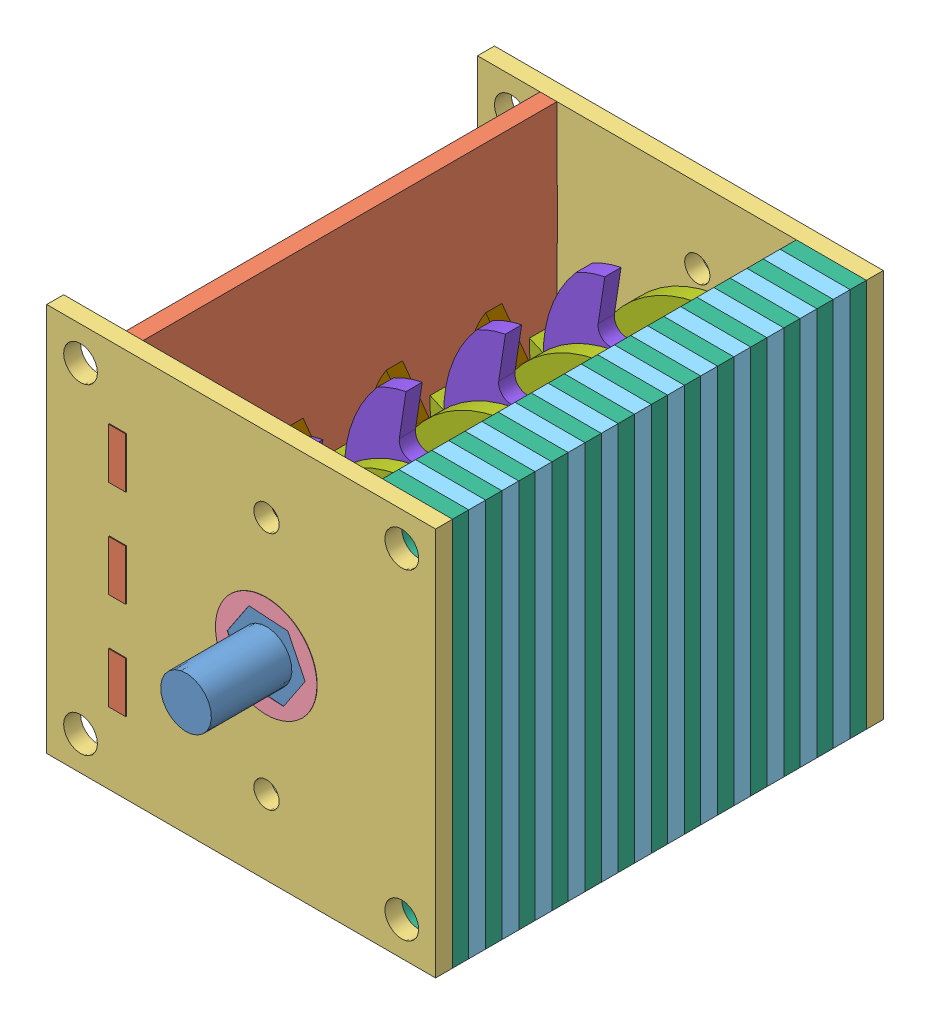
SolidWorks assembly Assem1, configuration Default. Lengths in mm.
Overall size (146.05 146.05 228.6).
56 component instances, 9 part files, 47 mates.
Components (placement in the parent):
- Axle-1: Axle [Default] at (0 0 80.899) x (-0.064462 -0.99792 0) z (0 0 1) size (25.4 29.33 228.6)
- BackPlate-1: BackPlate [Default] at (-55.88 0 80.899) x (0 0 -1) z (1 0 0) size (168.66 146.05 6.35)
- Side_Plate-1: Side_Plate [Default] at origin size (146.05 146.05 6.35)
- Side_Plate-2: Side_Plate [Default] at (0 0 161.798) size (146.05 146.05 6.35)
- Hex_Spacer-1: Hex_Spacer [Default] at (0 0 18.669) x (0.831993 -0.554786 0) z (0 0 1) size (38.1 38.1 6.35)
- Hex_Spacer-2: Hex_Spacer [Default] at (0 0 31.115) x (0.831993 -0.554786 0) z (0 0 1) size (38.1 38.1 6.35)
- Hex_Spacer-3: Hex_Spacer [Default] at (0 0 43.561) x (-0.831993 0.554786 0) z (0 0 1) size (38.1 38.1 6.35)
- Hex_Spacer-13: Hex_Spacer [Default] at (0 0 6.223) x (0.831993 -0.554786 0) z (0 0 1) size (38.1 38.1 6.35)
- Hex_Spacer-14: Hex_Spacer [Default] at (0 0 -0.127) x (0.831993 -0.554786 0) z (0 0 1) size (38.1 38.1 6.35)
- Hex_Spacer-15: Hex_Spacer [Default] at (0 0 161.925) x (0.831993 -0.554786 0) z (0 0 1) size (38.1 38.1 6.35)
- Spacer_1-1: Spacer_1 [Default] at (44.45 0 12.446) size (34.77 146.05 6.35)
- Spacer_2-1: Spacer_2 [Default] at (44.45 0 6.223) size (59.73 146.05 6.1)
- Spacer_2-14: Spacer_2 [Default] at (44.45 0 155.575) size (59.73 146.05 6.1)
- Spacer_2-2: Spacer_2 [Default] at (44.45 0 18.669) size (59.73 146.05 6.1)
- Spacer_2-3: Spacer_2 [Default] at (44.45 0 31.115) size (59.73 146.05 6.1)
- Spacer_2-4: Spacer_2 [Default] at (44.45 0 43.561) size (59.73 146.05 6.1)
- Spacer_2-5: Spacer_2 [Default] at (44.45 0 56.007) size (59.73 146.05 6.1)
- Spacer_2-6: Spacer_2 [Default] at (44.45 0 68.453) size (59.73 146.05 6.1)
- Spacer_2-7: Spacer_2 [Default] at (44.45 0 80.899) size (59.73 146.05 6.1)
- Spacer_2-8: Spacer_2 [Default] at (44.45 0 93.345) size (59.73 146.05 6.1)
- Spacer_2-9: Spacer_2 [Default] at (44.45 0 105.791) size (59.73 146.05 6.1)
- Spacer_2-10: Spacer_2 [Default] at (44.45 0 118.237) size (59.73 146.05 6.1)
- Spacer_2-11: Spacer_2 [Default] at (44.45 0 130.683) size (59.73 146.05 6.1)
- Spacer_2-12: Spacer_2 [Default] at (44.45 0 143.129) size (59.73 146.05 6.1)
- Spacer_1-3: Spacer_1 [Default] at (44.45 0 24.892) size (34.77 146.05 6.35)
- Spacer_1-4: Spacer_1 [Default] at (44.45 0 37.338) size (34.77 146.05 6.35)
- Spacer_1-5: Spacer_1 [Default] at (44.45 0 49.784) size (34.77 146.05 6.35)
- Spacer_1-6: Spacer_1 [Default] at (44.45 0 62.23) size (34.77 146.05 6.35)
- Spacer_1-7: Spacer_1 [Default] at (44.45 0 74.676) size (34.77 146.05 6.35)
- Spacer_1-8: Spacer_1 [Default] at (44.45 0 87.122) size (34.77 146.05 6.35)
- Spacer_1-9: Spacer_1 [Default] at (44.45 0 99.568) size (34.77 146.05 6.35)
- Spacer_1-10: Spacer_1 [Default] at (44.45 0 112.014) size (34.77 146.05 6.35)
- Spacer_1-11: Spacer_1 [Default] at (44.45 0 124.46) size (34.77 146.05 6.35)
- Spacer_1-12: Spacer_1 [Default] at (44.45 0 136.906) size (34.77 146.05 6.35)
- Spacer_1-13: Spacer_1 [Default] at (44.45 0 149.352) size (34.77 146.05 6.35)
- Cutter_1-1: Cutter_1 [Default] at (0 0 12.446) x (-0.064462 -0.99792 0) z (0.99792 -0.064462 0) size (280.09 6.1 281.96)
- Cutter_2-1: Cutter_2 [Default] at (0 0 24.892) x (0.660055 -0.751218 0) z (0.751218 0.660055 0) size (280.09 6.1 281.96)
- Cutter_3-1: Cutter_3 [Default] at (0 0 37.338) x (0.99792 -0.064462 0) z (0.064462 0.99792 0) size (280.09 6.1 281.96)
- Hex_Spacer-4: Hex_Spacer [Default] at (0 0 80.899) x (-0.831993 0.554786 0) z (0 0 1) size (38.1 38.1 6.35)
- Hex_Spacer-5: Hex_Spacer [Default] at (0 0 118.237) x (-0.831993 0.554786 0) z (0 0 1) size (38.1 38.1 6.35)
- Hex_Spacer-6: Hex_Spacer [Default] at (0 0 155.575) x (-0.831993 0.554786 0) z (0 0 1) size (38.1 38.1 6.35)
- Hex_Spacer-7: Hex_Spacer [Default] at (0 0 68.453) x (0.831993 -0.554786 0) z (0 0 1) size (38.1 38.1 6.35)
- Hex_Spacer-8: Hex_Spacer [Default] at (0 0 105.791) x (0.831993 -0.554786 0) z (0 0 1) size (38.1 38.1 6.35)
- Hex_Spacer-9: Hex_Spacer [Default] at (0 0 143.129) x (0.831993 -0.554786 0) z (0 0 1) size (38.1 38.1 6.35)
- Hex_Spacer-10: Hex_Spacer [Default] at (0 0 56.007) x (0.831993 -0.554786 0) z (0 0 1) size (38.1 38.1 6.35)
- Hex_Spacer-11: Hex_Spacer [Default] at (0 0 93.345) x (0.831993 -0.554786 0) z (0 0 1) size (38.1 38.1 6.35)
- Hex_Spacer-12: Hex_Spacer [Default] at (0 0 130.683) x (0.831993 -0.554786 0) z (0 0 1) size (38.1 38.1 6.35)
- Cutter_3-2: Cutter_3 [Default] at (0 0 74.676) x (0.99792 -0.064462 0) z (0.064462 0.99792 0) size (280.09 6.1 281.96)
- Cutter_3-3: Cutter_3 [Default] at (0 0 112.014) x (0.99792 -0.064462 0) z (0.064462 0.99792 0) size (280.09 6.1 281.96)
- Cutter_3-4: Cutter_3 [Default] at (0 0 149.352) x (0.99792 -0.064462 0) z (0.064462 0.99792 0) size (280.09 6.1 281.96)
- Cutter_2-2: Cutter_2 [Default] at (0 0 62.23) x (0.660055 -0.751218 0) z (0.751218 0.660055 0) size (280.09 6.1 281.96)
- Cutter_2-3: Cutter_2 [Default] at (0 0 99.568) x (0.660055 -0.751218 0) z (0.751218 0.660055 0) size (280.09 6.1 281.96)
- Cutter_2-4: Cutter_2 [Default] at (0 0 136.906) x (0.660055 -0.751218 0) z (0.751218 0.660055 0) size (280.09 6.1 281.96)
- Cutter_1-2: Cutter_1 [Default] at (0 0 49.784) x (-0.064462 -0.99792 0) z (0.99792 -0.064462 0) size (280.09 6.1 281.96)
- Cutter_1-3: Cutter_1 [Default] at (0 0 87.122) x (-0.064462 -0.99792 0) z (0.99792 -0.064462 0) size (280.09 6.1 281.96)
- Cutter_1-4: Cutter_1 [Default] at (0 0 124.46) x (-0.064462 -0.99792 0) z (0.99792 -0.064462 0) size (280.09 6.1 281.96)
Mates (geometry in assembly coordinates):
- Coincident15: coincident: plane of BackPlate-1 through (-55.88 0 80.899) normal (0 1 0); plane of assembly through (0 0 0) normal (0 1 0)
- Coincident19: coincident: plane of Side_Plate-1 through (0 0 0) normal (0 0 1); plane of assembly through (0 0 0) normal (0 0 1)
- Coincident20: coincident: plane of Side_Plate-1 through (0 0 0) normal (1 0 0); plane of assembly through (0 0 0) normal (1 0 0)
- Coincident21: coincident: plane of Side_Plate-1 through (0 0 0) normal (0 1 0); plane of assembly through (0 0 0) normal (0 1 0)
- Coincident22: coincident: plane of BackPlate-1 through (-55.88 0 80.899) normal (1 0 0); plane of assembly through (-55.88 0 0) normal (1 0 0)
- Coincident23: coincident: plane of BackPlate-1 through (-52.705 73.025 3.175) normal (0 0 -1); plane of Side_Plate-1 through (0 0 3.175) normal (0 0 1)
- Concentric9: concentric: cylinder of Axle-1 through (0 0 195.199) axis (0 0 -1) radius 9.525; cylinder of Side_Plate-1 through (0 0 3.175) axis (0 0 -1) radius 19.05
- Coincident25: coincident: line of Axle-1 through (-6.4984 13.1462 164.973) axis (0 0 -1); line of Hex_Spacer-1 through (-6.4984 13.1462 21.844) axis (0 0 -1)
- Coincident26: coincident: line of Axle-1 through (6.4984 -13.1462 164.973) axis (0 0 -1); line of Hex_Spacer-1 through (6.4984 -13.1462 21.844) axis (0 0 -1)
- Concentric14: concentric: cylinder of Side_Plate-1 through (50.8 -60.325 3.175) axis (0 0 -1) radius 6.35; cylinder of Spacer_1-1 through (50.8 -60.325 15.621) axis (0 0 -1) radius 6.3627
- Coincident30: coincident: line of Axle-1 through (-6.4984 13.1462 164.973) axis (0 0 -1); line of Cutter_1-1 through (-6.4984 13.1462 9.398) axis (0 0 1)
- Coincident31: coincident: line of Axle-1 through (14.6342 -0.9453 164.973) axis (0 0 -1); line of Cutter_1-1 through (14.6342 -0.9453 9.398) axis (0 0 1)
- Concentric15: concentric: cylinder of Side_Plate-1 through (50.8 60.325 3.175) axis (0 0 -1) radius 6.35; cylinder of Spacer_1-1 through (50.8 60.325 15.621) axis (0 0 -1) radius 6.3627
- Concentric16: concentric: cylinder of Side_Plate-1 through (50.8 60.325 3.175) axis (0 0 -1) radius 6.35; cylinder of Spacer_2-1 through (50.8 60.325 9.271) axis (0 0 -1) radius 6.3627
- Concentric17: concentric: cylinder of Side_Plate-1 through (50.8 -60.325 3.175) axis (0 0 -1) radius 6.35; cylinder of Spacer_2-1 through (50.8 -60.325 9.271) axis (0 0 -1) radius 6.3627
- Coincident38: coincident: plane of Side_Plate-1 through (0 0 3.175) normal (0 0 1); plane of Spacer_2-1 through (44.45 0 3.175) normal (0 0 -1)
- Coincident39: coincident: plane of Spacer_1-1 through (44.45 0 9.271) normal (0 0 -1); plane of Spacer_2-1 through (44.45 0 9.271) normal (0 0 1)
- Coincident40: coincident: plane of Spacer_1-13 through (44.45 0 152.527) normal (0 0 1); plane of Spacer_2-14 through (44.45 0 152.527) normal (0 0 -1)
- Concentric19: concentric: cylinder of Side_Plate-1 through (50.8 -60.325 3.175) axis (0 0 -1) radius 6.35; cylinder of Spacer_2-14 through (50.8 -60.325 158.623) axis (0 0 -1) radius 6.3627
- Concentric20: concentric: cylinder of Side_Plate-1 through (50.8 60.325 3.175) axis (0 0 -1) radius 6.35; cylinder of Spacer_2-14 through (50.8 60.325 158.623) axis (0 0 -1) radius 6.3627
- Coincident41: coincident: plane of Spacer_2-14 through (44.45 0 158.623) normal (0 0 1); plane of Side_Plate-2 through (0 0 158.623) normal (0 0 -1)
- Concentric22: concentric: cylinder of Side_Plate-1 through (50.8 60.325 3.175) axis (0 0 -1) radius 6.35; cylinder of Side_Plate-2 through (50.8 60.325 164.973) axis (0 0 -1) radius 6.35
- Concentric23: concentric: cylinder of Side_Plate-1 through (50.8 -60.325 3.175) axis (0 0 -1) radius 6.35; cylinder of Side_Plate-2 through (50.8 -60.325 164.973) axis (0 0 -1) radius 6.35
- Coincident42: coincident: plane of Spacer_1-1 through (44.45 0 12.446) normal (0 0 1); plane of Cutter_1-1 through (0 0 12.446) normal (0 0 -1)
- Coincident43: coincident: plane of Hex_Spacer-1 through (0 0 15.494) normal (0 0 -1); plane of Cutter_1-1 through (0 0 15.494) normal (0 0 1)
- Coincident44: coincident: line of Axle-1 through (14.6342 -0.9453 164.973) axis (0 0 -1); line of Hex_Spacer-2 through (14.6342 -0.9453 34.29) axis (0 0 -1)
- Coincident45: coincident: line of Axle-1 through (-14.6342 0.9453 164.973) axis (0 0 -1); line of Hex_Spacer-2 through (-14.6342 0.9453 34.29) axis (0 0 -1)
- Coincident47: coincident: line of Axle-1 through (-14.6342 0.9453 164.973) axis (0 0 -1); line of Cutter_2-1 through (-14.6342 0.9453 21.844) axis (0 0 1)
- Coincident48: coincident: line of Axle-1 through (6.4984 -13.1462 164.973) axis (0 0 -1); line of Cutter_2-1 through (6.4984 -13.1462 21.844) axis (0 0 1)
- Coincident49: coincident: plane of Hex_Spacer-1 through (0 0 21.844) normal (0 0 1); plane of Cutter_2-1 through (0 0 21.844) normal (0 0 -1)
- Coincident50: coincident: plane of Hex_Spacer-2 through (0 0 27.94) normal (0 0 -1); plane of Cutter_2-1 through (0 0 27.94) normal (0 0 1)
- Coincident51: coincident: line of Axle-1 through (14.6342 -0.9453 164.973) axis (0 0 -1); line of Cutter_3-1 through (14.6342 -0.9453 34.29) axis (0 0 1)
- Coincident52: coincident: line of Axle-1 through (-8.1358 -12.2009 164.973) axis (0 0 -1); line of Cutter_3-1 through (-8.1358 -12.2009 34.29) axis (0 0 1)
- Coincident53: coincident: plane of Hex_Spacer-2 through (0 0 34.29) normal (0 0 1); plane of Cutter_3-1 through (0 0 34.29) normal (0 0 -1)
- Coincident54: coincident: line of Axle-1 through (-8.1358 -12.2009 164.973) axis (0 0 -1); line of Hex_Spacer-3 through (-8.1358 -12.2009 46.736) axis (0 0 -1)
- Coincident55: coincident: line of Axle-1 through (14.6342 -0.9453 164.973) axis (0 0 -1); line of Hex_Spacer-3 through (14.6342 -0.9453 46.736) axis (0 0 -1)
- Coincident56: coincident: plane of Cutter_3-1 through (0 0 40.386) normal (0 0 1); plane of Hex_Spacer-3 through (0 0 40.386) normal (0 0 -1)
- Coincident57: coincident: plane of Axle-1 through (0 0 -3.175) normal (0 0 -1); plane of Side_Plate-1 through (0 0 -3.175) normal (0 0 -1)
- Coincident58: coincident: line of Axle-1 through (14.6342 -0.9453 164.973) axis (0 0 -1); line of Hex_Spacer-13 through (14.6342 -0.9453 9.398) axis (0 0 -1)
- Coincident59: coincident: line of Axle-1 through (-14.6342 0.9453 164.973) axis (0 0 -1); line of Hex_Spacer-13 through (-14.6342 0.9453 9.398) axis (0 0 -1)
- Coincident60: coincident: plane of Cutter_1-1 through (0 0 9.398) normal (0 0 -1); plane of Hex_Spacer-13 through (0 0 9.398) normal (0 0 1)
- Coincident61: coincident: line of Axle-1 through (14.6342 -0.9453 164.973) axis (0 0 -1); line of Hex_Spacer-14 through (14.6342 -0.9453 3.048) axis (0 0 -1)
- Coincident62: coincident: line of Axle-1 through (-14.6342 0.9453 164.973) axis (0 0 -1); line of Hex_Spacer-14 through (-14.6342 0.9453 3.048) axis (0 0 -1)
- Coincident63: coincident: plane of Hex_Spacer-13 through (0 0 3.048) normal (0 0 -1); plane of Hex_Spacer-14 through (0 0 3.048) normal (0 0 1)
- Coincident64: coincident: line of Axle-1 through (14.6342 -0.9453 164.973) axis (0 0 -1); line of Hex_Spacer-15 through (14.6342 -0.9453 165.1) axis (0 0 -1)
- Coincident65: coincident: line of Axle-1 through (-14.6342 0.9453 164.973) axis (0 0 -1); line of Hex_Spacer-15 through (-14.6342 0.9453 165.1) axis (0 0 -1)
- Coincident66: coincident: plane of Hex_Spacer-6 through (0 0 158.75) normal (0 0 1); plane of Hex_Spacer-15 through (0 0 158.75) normal (0 0 -1)
